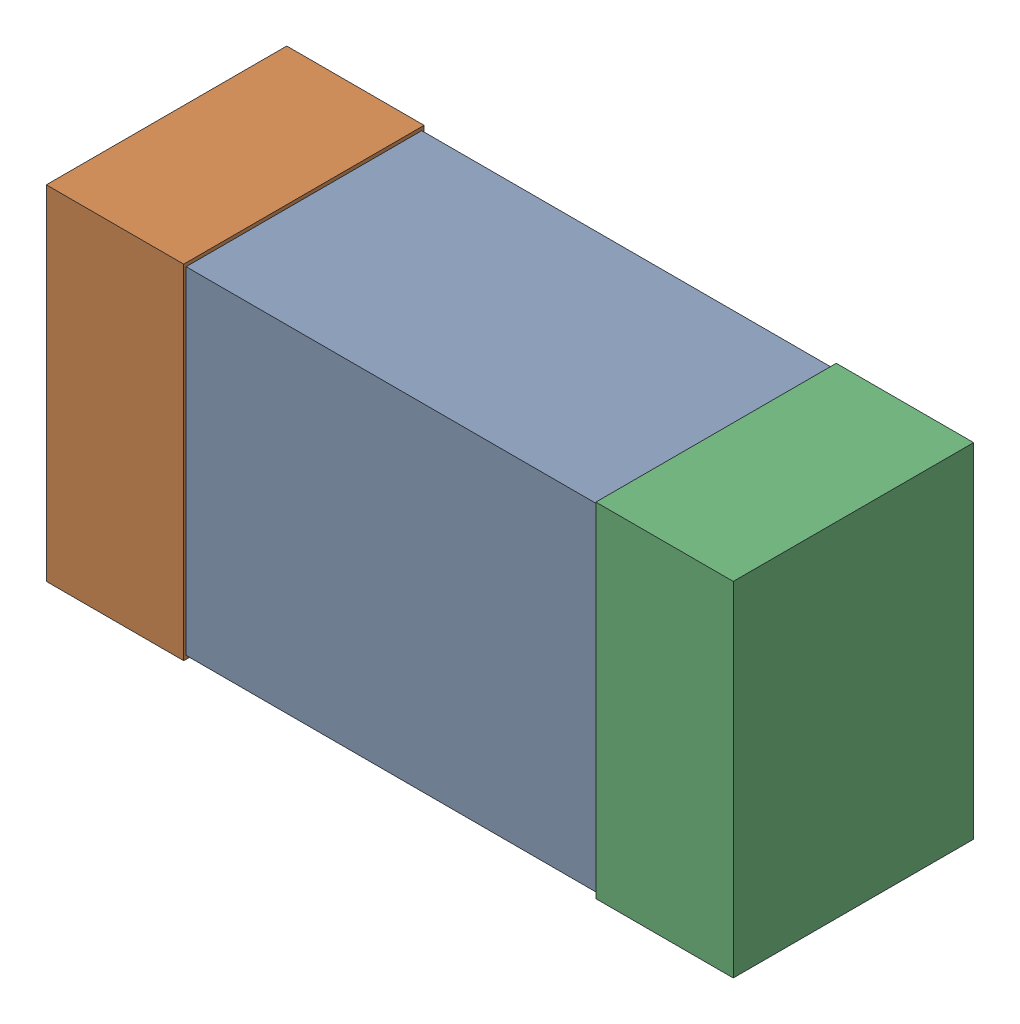
SolidWorks assembly R2, configuration Predeterminado. Lengths in mm.
Overall size (1 0.5 0.35).
4 component instances, 3 part files, 0 mates.
Components (placement in the parent):
- 6074689680-1: 6074689680 [Predeterminado] at (30.5 40 0) x (-1 0 0) z (0 0 1) size (1 0.5 0.35)
  - body-2-1: body-2 [Predeterminado] at (-0.3 -0.245 0.0035) size (0.6 0.49 0.34)
  - term2-1-1: term2-1 [Predeterminado] at (0.3 -0.25 0) size (0.2 0.5 0.35)
  - term1-1-1: term1-1 [Predeterminado] at (-0.5 -0.25 0) size (0.2 0.5 0.35)
